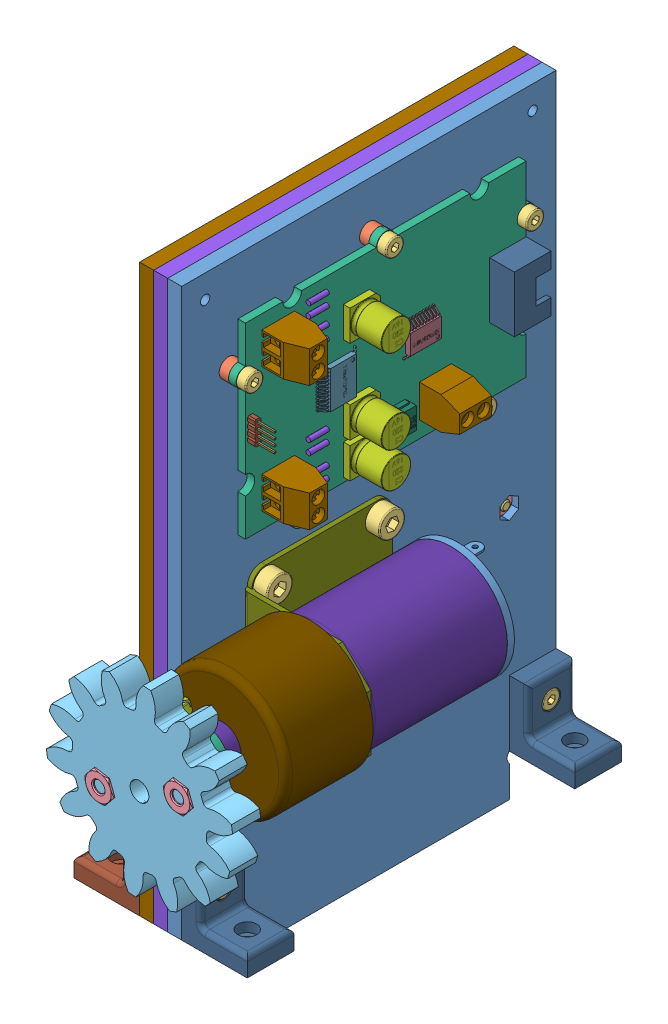
SolidWorks assembly moteur-complet, configuration Défaut. Lengths in mm.
Overall size (62.95 130 103.93).
88 component instances, 29 part files, 109 mates.
Components (placement in the parent):
- moteur-platine-1-4: moteur-platine-1 [Défaut] at (-59.9962 -68.9698 170) size (3 130 80)
- Grove button-1: Grove button [Défaut] at (-66.7015 -12.8903 110) x (0 -1 0) z (0 0 -1) size (20 11.6 23.6)
  - PCB grove 20x20-1: PCB grove 20x20 [Défaut] at (2.0795 1.2947 0) size (20 1.6 23.6)
  - 603 resistor 102-1: 603 resistor 102 [Default] at (2.0895 2.8947 -6.319) x (0 0 1) z (-1 0 0) size (2.36 0.62 1.03)
  - tactileswitch-CMS-1: tactileswitch-CMS [Default] at (-2.4169 2.8947 0.0035) x (0 0 1) z (-1 0 0) size (8.41 4.95 6.01)
  - Connecteur Grove (droit CMS)-1: Connecteur Grove (droit CMS) [Défaut] at (5.0795 2.8947 0) x (-1 0 0) z (0 1 0) size (6.5 14 10)
  - 603 resistor 102-2: 603 resistor 102 [Default] at (3.5895 2.8947 -6.319) x (0 0 1) z (-1 0 0) size (2.36 0.62 1.03)
- Grove I2C Motor driver TB6612FNG-1: Grove I2C Motor driver TB6612FNG [Défaut] at (-118.1962 28.5169 135.6463) x (0 0 1) z (1 0 0) size (64 44 12.2)
  - Plaque de base-1: Plaque de base [Défaut] at (-5.6463 -2.5133 63.2) size (64 44 1.6)
  - CS 220 16V-1: CS 220 16V [Défaut] at (0.1237 13.2167 64.8) x (1 0 0) z (0 -1 0) size (6.54 8.01 6.54)
  - CS 220 16V-2: CS 220 16V [Défaut] at (0.1237 5.6767 64.8) x (1 0 0) z (0 -1 0) size (6.54 8.01 6.54)
  - CS 220 16V-3: CS 220 16V [Défaut] at (0.1237 -12.2433 64.8) x (1 0 0) z (0 -1 0) size (6.54 8.01 6.54)
  - D1-1: D1 [Défaut] at (7.4081 5.2819 65.3) x (0 0.946795 -0.321836) z (1 0 0) size (1 1 4)
  - D1-2: D1 [Défaut] at (7.4081 7.7235 65.3) x (0 0.786026 0.618193) z (1 0 0) size (1 1 4)
  - D1-3: D1 [Défaut] at (7.4081 14.4025 65.3) x (0 0.953842 0.300308) z (1 0 0) size (1 1 4)
  - D1-4: D1 [Défaut] at (7.4081 11.9602 65.3) x (0 0.659384 0.751806) z (1 0 0) size (1 1 4)
  - D1-5: D1 [Défaut] at (7.4081 -17.5815 65.3) x (0 -0.999835 -0.018161) z (1 0 0) size (1 1 4)
  - D1-6: D1 [Défaut] at (7.4081 -14.133 65.3) x (0 0.806812 -0.590809) z (1 0 0) size (1 1 4)
  - D1-7: D1 [Défaut] at (7.4081 -11.4343 65.3) x (0 -0.166774 0.985995) z (1 0 0) size (1 1 4)
  - D1-8: D1 [Défaut] at (7.4081 -20.0356 65.3) x (0 0.962631 -0.270816) z (1 0 0) size (1 1 4)
  - bornier double-1: bornier double [Défaut] at (20.8537 7.1995 64.8) x (0 1 0) z (1 0 0) size (6.8 12.2 7)
  - bornier double-2: bornier double [Défaut] at (-12.8463 13.9867 64.8) x (-1 0 0) z (0 1 0) size (6.8 12.2 7)
  - bornier double-3: bornier double [Défaut] at (20.8537 -19.5133 64.8) x (0 1 0) z (1 0 0) size (6.8 12.2 7)
  - Grove Connecteur-1: Grove Connecteur [Défaut] at (-37.0963 -2.5133 64.05) x (1 0 0) z (0 -1 0) size (7.8 5.3 12)
  - Bloc 4 pins male-1: Bloc 4 pins male [Défaut] at (23.2493 -0.7812 63.276) x (0 -1 0) z (0 0 1) size (5.08 1.27 7.62)
    - Pin_cmi2c_Base-1: Pin_cmi2c_Base [Défaut] at (-0.1729 -0.0306 1.524) size (1.27 1.27 1.52)
    - Pin_cmi2c-1: Pin_cmi2c [Défaut] at (-0.1729 0.1472 -0.762) x (1 0 0) z (0 -1 0) size (0.36 7.62 0.36)
    - Pin_cmi2c-2: Pin_cmi2c [Défaut] at (1.0971 0.1472 -0.762) x (1 0 0) z (0 -1 0) size (0.36 7.62 0.36)
    - Pin_cmi2c-3: Pin_cmi2c [Défaut] at (2.3671 0.1472 -0.762) x (1 0 0) z (0 -1 0) size (0.36 7.62 0.36)
    - Pin_cmi2c-4: Pin_cmi2c [Défaut] at (3.6371 0.1472 -0.762) x (1 0 0) z (0 -1 0) size (0.36 7.62 0.36)
    - Pin_cmi2c_Base-2: Pin_cmi2c_Base [Défaut] at (1.0971 -0.0306 1.524) size (1.27 1.27 1.52)
    - Pin_cmi2c_Base-3: Pin_cmi2c_Base [Défaut] at (2.3671 -0.0306 1.524) size (1.27 1.27 1.52)
    - Pin_cmi2c_Base-4: Pin_cmi2c_Base [Défaut] at (3.6371 -0.0306 1.524) size (1.27 1.27 1.52)
  - Microcontroller 32F030F4P6-1: Microcontroller 32F030F4P6 [Défaut] at (-12.4961 -2.5519 65.5199) size (6.61 6.93 1.72)
  - Microcontroller TB6612FNG-1: Microcontroller TB6612FNG [Défaut] at (5.1421 -2.7086 65.5199) x (0 1 0) z (0 0 1) size (8 8.26 1.72)
  - PK13-1: PK13 [Défaut] at (-8.5328 11.2953 64.8) x (0 -1 0) z (-1 0 0) size (5.33 2 3.32)
- moteur MFA-1: moteur MFA [Défaut] at (-44.4916 -13.5198 141.6132) x (0 0 -1) z (0 -1 0) size (69.13 27.9 30)
  - moteur-support-1: moteur-support [Défaut] at (-14.3868 -12.5047 0) size (31 26.4 30)
  - moteur-corps-1: moteur-corps [Défaut] at (14.8132 1.8953 0) x (0 0 1) z (-1 0 0) size (24 24 62.63)
  - moteur-capuchon-1: moteur-capuchon [Défaut] at (-15.3868 1.8953 0) x (0 0 1) z (-1 0 0) size (27 27 18.7)
  - moteur-arriere-1: moteur-arriere [Défaut] at (16.3132 1.8953 0) x (0 0 1) z (-1 0 0) size (24 24 6.5)
- entretoise-grove-1: entretoise-grove [Défaut] at (-54.9962 51.0302 130) x (0 0.271539 0.962428) z (-1 0 0) size (4 4 2)
- entretoise-grove-2: entretoise-grove [Défaut] at (-54.9962 41.0302 100) x (0 0.358036 0.933708) z (-1 0 0) size (4 4 2)
- entretoise-grove-3: entretoise-grove [Défaut] at (-54.9962 41.0302 160) x (0 -0.42455 0.905404) z (-1 0 0) size (4 4 2)
- entretoise-grove-4: entretoise-grove [Défaut] at (-54.9962 11.0302 150) x (0 0 1) z (-1 0 0) size (4 4 2)
- entretoise-grove-5: entretoise-grove [Défaut] at (-54.9962 11.0302 110) x (0 0.014886 0.999889) z (-1 0 0) size (4 4 2)
- entretoise-grove-6: entretoise-grove [Défaut] at (-67.9962 -14.9698 120) x (0 0.014606 -0.999893) z (1 0 0) size (4 4 2)
- entretoise-grove-7: entretoise-grove [Défaut] at (-67.9962 -14.9698 100) x (0 0.432952 0.901417) z (1 0 0) size (4 4 2)
- vis-chc-1: vis-chc [Vis CHC M2x12] at (-69.5962 -14.9698 100) x (0 0.697993 -0.716105) z (0 0.716105 0.697993) size (3.8 14 3.8)
- vis-chc-2: vis-chc [Vis CHC M2x12] at (-69.5962 -14.9698 120) x (0 0.185382 -0.982666) z (0 0.982666 0.185382) size (3.8 14 3.8)
- vis-chc-3: vis-chc [Vis CHC M2x12] at (-53.3962 41.0302 100) x (0 0.381849 -0.924225) z (0 -0.924225 -0.381849) size (3.8 14 3.8)
- vis-chc-4: vis-chc [Vis CHC M2x12] at (-53.3962 51.0302 130) x (0 0.381849 -0.924225) z (0 -0.924225 -0.381849) size (3.8 14 3.8)
- vis-chc-5: vis-chc [Vis CHC M2x12] at (-53.3962 41.0302 160) x (0 0.381849 -0.924225) z (0 -0.924225 -0.381849) size (3.8 14 3.8)
- vis-chc-6: vis-chc [Vis CHC M2x12] at (-53.3962 11.0302 150) x (0 0.381849 -0.924225) z (0 -0.924225 -0.381849) size (3.8 14 3.8)
- vis-chc-7: vis-chc [Vis CHC M2x12] at (-53.3962 11.0302 110) x (0 0.381849 -0.924225) z (0 -0.924225 -0.381849) size (3.8 14 3.8)
- ecrou-h-2: ecrou-h [6007 HU M2] at (-59.9962 -14.9698 120) x (0 0.866025 0.5) z (0 -0.5 0.866025) size (4 1.6 4.62)
- ecrou-h-3: ecrou-h [6007 HU M2] at (-59.9962 -14.9698 100) x (0 0 1) z (0 -1 0) size (4 1.6 4.62)
- ecrou-h-4: ecrou-h [6007 HU M2] at (-64.5962 11.0302 110) x (0 0.866025 0.5) z (0 -0.5 0.866025) size (4 1.6 4.62)
- ecrou-h-5: ecrou-h [6007 HU M2] at (-64.5962 11.0302 150) x (0 0.866025 0.5) z (0 -0.5 0.866025) size (4 1.6 4.62)
- ecrou-h-6: ecrou-h [6007 HU M2] at (-64.5962 41.0302 160) x (0 0.866025 0.5) z (0 -0.5 0.866025) size (4 1.6 4.62)
- ecrou-h-7: ecrou-h [6007 HU M2] at (-64.5962 51.0302 130) x (0 0.866025 0.5) z (0 -0.5 0.866025) size (4 1.6 4.62)
- ecrou-h-8: ecrou-h [6007 HU M2] at (-64.5962 41.0302 100) x (0 0.866025 0.5) z (0 -0.5 0.866025) size (4 1.6 4.62)
- vis-chc-8: vis-chc [Vis CHC M3x10] at (-55.9962 -1.5198 129) x (0 0.773717 -0.633531) z (0 -0.633531 -0.773717) size (5.5 13 5.5)
- vis-chc-9: vis-chc [Vis CHC M3x10] at (-55.9962 -1.5198 153) x (0 0.483049 -0.875594) z (0 -0.875594 -0.483049) size (5.5 13 5.5)
- vis-chc-10: vis-chc [Vis CHC M3x10] at (-55.9962 -25.5198 153) x (0 0.381849 -0.924225) z (0 -0.924225 -0.381849) size (5.5 13 5.5)
- vis-chc-11: vis-chc [Vis CHC M3x10] at (-55.9962 -25.5198 129) x (0 0.381849 -0.924225) z (0 -0.924225 -0.381849) size (5.5 13 5.5)
- ecrou-h-9: ecrou-h [6012 HU M3] at (-65.3962 -1.5198 153) x (0 0.866025 0.5) z (0 -0.5 0.866025) size (5.5 2.4 6.35)
- ecrou-h-10: ecrou-h [6012 HU M3] at (-65.3962 -25.5198 153) x (0 0.866025 0.5) z (0 -0.5 0.866025) size (5.5 2.4 6.35)
- ecrou-h-11: ecrou-h [6012 HU M3] at (-65.3962 -25.5198 129) x (0 0.866025 -0.5) z (0 0.5 0.866025) size (5.5 2.4 6.35)
- ecrou-h-12: ecrou-h [6012 HU M3] at (-65.3962 -1.5198 129) x (0 0.866025 -0.5) z (0 0.5 0.866025) size (5.5 2.4 6.35)
- vis-chc-14: vis-chc [Vis CHC M2x16] at (-54.9962 -50.9698 95) x (0 -0.431797 -0.901971) z (0 -0.901971 0.431797) size (3.8 18 3.8)
- vis-chc-15: vis-chc [Vis CHC M2x16] at (-54.9962 -50.9698 165) x (0 0.381849 -0.924225) z (0 -0.924225 -0.381849) size (3.8 18 3.8)
- ecrou-h-15: ecrou-h [6007 HU M2] at (-69.5962 -50.9698 165) x (0 1 0) z (0 0 1) size (4 1.6 4.62)
- ecrou-h-16: ecrou-h [6007 HU M2] at (-69.5962 -50.9698 95) x (0 0.5 0.866025) z (0 -0.866025 0.5) size (4 1.6 4.62)
- engrenage-complet-1: engrenage-complet [Défaut] at (-42.1676 -13.7474 193.43) x (0.932852 0.36026 0) z (0 0 -1) size (39.32 40 14.86)
  - engrenage-1: engrenage [Défaut] at (1.0609 0.1936 0) size (39.32 40 6)
  - engrenage-bague_arret-1: engrenage-bague_arret [Défaut] at (-0.3178 -0.3667 13.5) x (-1 0 0) z (0 0 -1) size (24 24 8)
  - vis-tc-m3x6-1: vis-tc-m3x6 [Défaut] at (-0.3178 -8.4167 10.5) x (-0.611546 0 0.791209) z (0.791209 0 0.611546) size (5.5 7.83 5.5)
  - vis-chc-1: vis-chc [Vis CHC M3x8] at (-9.3178 -0.3667 7.5) x (0.40091 -0.916118 0) z (-0.916118 -0.40091 0) size (5.5 11 5.5)
  - vis-chc-2: vis-chc [Vis CHC M3x8] at (8.6822 -0.3667 7.5) x (0.998484 0.055044 0) z (0.055044 -0.998484 0) size (5.5 11 5.5)
  - ecrou-h-1: ecrou-h [6012 HU M3] at (8.6822 -0.3667 -0.4) x (1 0 0) z (0 1 0) size (5.5 2.4 6.35)
  - ecrou-h-2: ecrou-h [6012 HU M3] at (-9.3178 -0.3667 -0.4) x (1 0 0) z (0 1 0) size (5.5 2.4 6.35)
- moteur-platine-2-5: moteur-platine-2 [Défaut] at (-62.9962 -68.9698 170) size (3 130 80)
- moteur-platine-3-3: moteur-platine-3 [Défaut] at (-65.9962 -68.9698 170) size (3 130 80)
- equerre-3: equerre [Défaut] at (-56.9962 -59.9698 165) x (0 0 -1) z (1 0 0) size (10 14 14)
- equerre-2: equerre [Défaut] at (-56.9962 -59.9698 95) x (0 0 -1) z (1 0 0) size (10 14 14)
- equerre-ecrou-1: equerre-ecrou [Défaut] at (-65.9962 -59.9698 95) x (0 0 1) z (-1 0 0) size (10 14 14)
- equerre-ecrou-2: equerre-ecrou [Défaut] at (-65.9962 -59.9698 165) x (0 0 1) z (-1 0 0) size (10 14 14)
Mates (geometry in assembly coordinates):
- Coïncidente1: coincident anti-aligned: plane of moteur-platine-1-4 through (-56.9962 -61.1012 161.1314) normal (1 0 0); plane of moteur MFA-1/moteur-support-1 through (-56.9962 -25.5198 153) normal (-1 0 0)
- Coaxiale1: concentric anti-aligned: cylinder of moteur-platine-1-4 through (-59.9962 -1.5198 129) axis (1 0 0) radius 1.6; cylinder of moteur MFA-1/moteur-support-1 through (-30.5962 -1.5198 129) axis (-1 0 0) radius 1.65
- Coaxiale2: concentric anti-aligned: cylinder of moteur-platine-1-4 through (-59.9962 -25.5198 129) axis (1 0 0) radius 1.6; cylinder of moteur MFA-1/moteur-support-1 through (-30.5962 -25.5198 129) axis (-1 0 0) radius 1.65
- Parallèle1: parallel aligned: plane of moteur-platine-1-4 through (-56.9962 61.0302 90) normal (0 0 -1); plane of Grove I2C Motor driver TB6612FNG-1/Plaque de base-1 through (-53.3962 11.0302 100) normal (0 0 -1)
- Parallèle2: parallel aligned: plane of moteur-platine-1-4 through (-56.9962 61.0302 170) normal (0 1 0); plane of Grove I2C Motor driver TB6612FNG-1/Plaque de base-1 through (-53.3962 51.0302 132) normal (0 1 0)
- Coaxiale3: concentric anti-aligned: cylinder of Grove I2C Motor driver TB6612FNG-1/Plaque de base-1 through (-53.3962 11.0302 110) axis (-1 0 0) radius 1; cylinder of entretoise-grove-5 through (-56.9962 11.0302 110) axis (1 0 0) radius 1.1
- Coïncidente4: coincident anti-aligned: plane of Grove I2C Motor driver TB6612FNG-1/Plaque de base-1 through (-54.9962 21.0302 100) normal (-1 0 0); plane of entretoise-grove-5 through (-54.9962 11.0302 110) normal (1 0 0)
- Coaxiale4: concentric anti-aligned: cylinder of Grove I2C Motor driver TB6612FNG-1/Plaque de base-1 through (-53.3962 11.0302 150) axis (-1 0 0) radius 1; cylinder of entretoise-grove-4 through (-56.9962 11.0302 150) axis (1 0 0) radius 1.1
- Coïncidente5: coincident anti-aligned: plane of Grove I2C Motor driver TB6612FNG-1/Plaque de base-1 through (-54.9962 21.0302 100) normal (-1 0 0); plane of entretoise-grove-4 through (-54.9962 11.0302 150) normal (1 0 0)
- Coaxiale5: concentric anti-aligned: cylinder of Grove I2C Motor driver TB6612FNG-1/Plaque de base-1 through (-53.3962 41.0302 100) axis (-1 0 0) radius 1; cylinder of entretoise-grove-2 through (-56.9962 41.0302 100) axis (1 0 0) radius 1.1
- Coïncidente6: coincident anti-aligned: plane of Grove I2C Motor driver TB6612FNG-1/Plaque de base-1 through (-54.9962 21.0302 100) normal (-1 0 0); plane of entretoise-grove-2 through (-54.9962 41.0302 100) normal (1 0 0)
- Coaxiale6: concentric anti-aligned: cylinder of Grove I2C Motor driver TB6612FNG-1/Plaque de base-1 through (-53.3962 41.0302 160) axis (-1 0 0) radius 1; cylinder of entretoise-grove-3 through (-56.9962 41.0302 160) axis (1 0 0) radius 1.1
- Coïncidente7: coincident anti-aligned: plane of Grove I2C Motor driver TB6612FNG-1/Plaque de base-1 through (-54.9962 21.0302 100) normal (-1 0 0); plane of entretoise-grove-3 through (-54.9962 41.0302 160) normal (1 0 0)
- Coaxiale7: concentric anti-aligned: cylinder of Grove I2C Motor driver TB6612FNG-1/Plaque de base-1 through (-53.3962 51.0302 130) axis (-1 0 0) radius 1; cylinder of entretoise-grove-1 through (-56.9962 51.0302 130) axis (1 0 0) radius 1.1
- Coïncidente8: coincident anti-aligned: plane of Grove I2C Motor driver TB6612FNG-1/Plaque de base-1 through (-54.9962 21.0302 100) normal (-1 0 0); plane of entretoise-grove-1 through (-54.9962 51.0302 130) normal (1 0 0)
- Coïncidente9: coincident anti-aligned: plane of moteur-platine-1-4 through (-56.9962 -61.1012 161.1314) normal (1 0 0); plane of entretoise-grove-3 through (-56.9962 41.0302 160) normal (-1 0 0)
- Coaxiale8: concentric aligned: cylinder of moteur-platine-1-4 through (-59.9962 11.0302 150) axis (1 0 0) radius 1.1; cylinder of entretoise-grove-4 through (-56.9962 11.0302 150) axis (1 0 0) radius 1.1
- Coaxiale9: concentric anti-aligned: cylinder of Grove button-1/PCB grove 20x20-1 through (-69.5962 -14.9698 120) axis (1 0 0) radius 1.1; cylinder of entretoise-grove-6 through (-65.9962 -14.9698 120) axis (-1 0 0) radius 1.1
- Coaxiale10: concentric anti-aligned: cylinder of Grove button-1/PCB grove 20x20-1 through (-69.5962 -14.9698 100) axis (1 0 0) radius 1.1; cylinder of entretoise-grove-7 through (-65.9962 -14.9698 100) axis (-1 0 0) radius 1.1
- Coïncidente11: coincident anti-aligned: plane of Grove button-1/PCB grove 20x20-1 through (-67.9962 -14.9698 110) normal (1 0 0); plane of entretoise-grove-7 through (-67.9962 -14.9698 100) normal (-1 0 0)
- Coaxiale13: concentric anti-aligned: cylinder of moteur MFA-1/moteur-corps-1 through (-42.5962 -13.5198 189.43) axis (0 0 -1) radius 2; cylinder of engrenage-complet-1/engrenage-bague_arret-1 through (-42.5962 -13.5198 179.93) axis (0 0 1) radius 2.05
- Distance1: distance = 0.5 mm anti-aligned: plane of engrenage-complet-1/engrenage-bague_arret-1 through (-42.5962 -13.5198 179.93) normal (0 0 -1); plane of moteur MFA-1/moteur-corps-1 through (-42.5962 -13.5198 179.43) normal (0 0 1)
- Coïncidente12: coincident anti-aligned: plane of moteur-platine-1-4 through (-59.9962 -61.1012 161.1314) normal (-1 0 0); plane of moteur-platine-2-5 through (-59.9962 -61.1012 161.1314) normal (1 0 0)
- Coïncidente13: coincident aligned: plane of moteur-platine-1-4 through (-56.9962 61.0302 170) normal (0 1 0); plane of moteur-platine-2-5 through (-59.9962 61.0302 170) normal (0 1 0)
- Coïncidente14: coincident aligned: plane of moteur-platine-1-4 through (-56.9962 61.0302 90) normal (0 0 -1); plane of moteur-platine-2-5 through (-59.9962 61.0302 90) normal (0 0 -1)
- Coïncidente15: coincident anti-aligned: plane of moteur-platine-2-5 through (-62.9962 -61.1012 161.1314) normal (-1 0 0); plane of moteur-platine-3-3 through (-62.9962 -61.1012 161.1314) normal (1 0 0)
- Coïncidente16: coincident aligned: plane of moteur-platine-2-5 through (-59.9962 61.0302 170) normal (0 1 0); plane of moteur-platine-3-3 through (-62.9962 61.0302 170) normal (0 1 0)
- Coïncidente17: coincident aligned: plane of moteur-platine-1-4 through (-56.9962 61.0302 90) normal (0 0 -1); plane of moteur-platine-3-3 through (-62.9962 61.0302 90) normal (0 0 -1)
- Coïncidente18: coincident anti-aligned: plane of entretoise-grove-7 through (-65.9962 -14.9698 100) normal (1 0 0); plane of moteur-platine-3-3 through (-65.9962 -61.1012 161.1314) normal (-1 0 0)
- Coïncidente19: coincident anti-aligned: plane of entretoise-grove-6 through (-65.9962 -14.9698 120) normal (1 0 0); plane of moteur-platine-3-3 through (-65.9962 -61.1012 161.1314) normal (-1 0 0)
- Coïncidente21: coincident anti-aligned: plane of Grove button-1/PCB grove 20x20-1 through (-69.5962 -14.9698 110) normal (-1 0 0); plane of vis-chc-2 through (-69.5962 -14.9698 120) normal (1 0 0)
- Coaxiale15: concentric aligned: cylinder of vis-chc-2 through (-57.5962 -14.9698 120) axis (-1 0 0) radius 1; cylinder of ecrou-h-2 through (-58.3962 -14.9698 120) axis (-1 0 0) radius 0.7835
- Parallèle4: parallel aligned: plane of moteur-platine-1-4 through (-56.9962 61.0302 90) normal (0 0 -1); plane of ecrou-h-2 through (-58.3962 -13.8151 118) normal (0 0 -1)
- Coïncidente25: coincident anti-aligned: plane of Grove button-1/PCB grove 20x20-1 through (-69.5962 -14.9698 110) normal (-1 0 0); plane of vis-chc-1 through (-69.5962 -14.9698 100) normal (1 0 0)
- Coaxiale17: concentric aligned: cylinder of vis-chc-1 through (-57.5962 -14.9698 100) axis (-1 0 0) radius 1; cylinder of ecrou-h-3 through (-58.3962 -14.9698 100) axis (-1 0 0) radius 0.7835
- Parallèle5: parallel aligned: plane of moteur-platine-1-4 through (-56.9962 61.0302 90) normal (0 0 -1); plane of ecrou-h-3 through (-58.3962 -13.8151 98) normal (0 0 -1)
- Coaxiale18: concentric anti-aligned: cylinder of Grove I2C Motor driver TB6612FNG-1/Plaque de base-1 through (-53.3962 11.0302 110) axis (-1 0 0) radius 1; cylinder of vis-chc-7 through (-65.3962 11.0302 110) axis (1 0 0) radius 1
- Coaxiale19: concentric anti-aligned: cylinder of Grove I2C Motor driver TB6612FNG-1/Plaque de base-1 through (-53.3962 11.0302 150) axis (-1 0 0) radius 1; cylinder of vis-chc-6 through (-65.3962 11.0302 150) axis (1 0 0) radius 1
- Coaxiale20: concentric anti-aligned: cylinder of Grove I2C Motor driver TB6612FNG-1/Plaque de base-1 through (-53.3962 41.0302 160) axis (-1 0 0) radius 1; cylinder of vis-chc-5 through (-65.3962 41.0302 160) axis (1 0 0) radius 1
- Coaxiale21: concentric anti-aligned: cylinder of Grove I2C Motor driver TB6612FNG-1/Plaque de base-1 through (-53.3962 51.0302 130) axis (-1 0 0) radius 1; cylinder of vis-chc-4 through (-65.3962 51.0302 130) axis (1 0 0) radius 1
- Coaxiale22: concentric anti-aligned: cylinder of Grove I2C Motor driver TB6612FNG-1/Plaque de base-1 through (-53.3962 41.0302 100) axis (-1 0 0) radius 1; cylinder of vis-chc-3 through (-65.3962 41.0302 100) axis (1 0 0) radius 1
- Coïncidente28: coincident anti-aligned: plane of Grove I2C Motor driver TB6612FNG-1/Plaque de base-1 through (-53.3962 21.0302 100) normal (1 0 0); plane of vis-chc-3 through (-53.3962 41.0302 100) normal (-1 0 0)
- Coïncidente29: coincident anti-aligned: plane of Grove I2C Motor driver TB6612FNG-1/Plaque de base-1 through (-53.3962 21.0302 100) normal (1 0 0); plane of vis-chc-4 through (-53.3962 51.0302 130) normal (-1 0 0)
- Coïncidente30: coincident anti-aligned: plane of Grove I2C Motor driver TB6612FNG-1/Plaque de base-1 through (-53.3962 21.0302 100) normal (1 0 0); plane of vis-chc-5 through (-53.3962 41.0302 160) normal (-1 0 0)
- Coïncidente31: coincident anti-aligned: plane of Grove I2C Motor driver TB6612FNG-1/Plaque de base-1 through (-53.3962 21.0302 100) normal (1 0 0); plane of vis-chc-6 through (-53.3962 11.0302 150) normal (-1 0 0)
- Coïncidente32: coincident anti-aligned: plane of Grove I2C Motor driver TB6612FNG-1/Plaque de base-1 through (-53.3962 21.0302 100) normal (1 0 0); plane of vis-chc-7 through (-53.3962 11.0302 110) normal (-1 0 0)
- Coaxiale23: concentric anti-aligned: cylinder of vis-chc-7 through (-65.3962 11.0302 110) axis (1 0 0) radius 1; cylinder of ecrou-h-4 through (-62.9962 11.0302 110) axis (-1 0 0) radius 0.7835
- Coaxiale24: concentric anti-aligned: cylinder of vis-chc-3 through (-65.3962 41.0302 100) axis (1 0 0) radius 1; cylinder of ecrou-h-8 through (-62.9962 41.0302 100) axis (-1 0 0) radius 0.7835
- Coaxiale25: concentric anti-aligned: cylinder of vis-chc-4 through (-65.3962 51.0302 130) axis (1 0 0) radius 1; cylinder of ecrou-h-7 through (-62.9962 51.0302 130) axis (-1 0 0) radius 0.7835
- Coaxiale26: concentric anti-aligned: cylinder of vis-chc-5 through (-65.3962 41.0302 160) axis (1 0 0) radius 1; cylinder of ecrou-h-6 through (-62.9962 41.0302 160) axis (-1 0 0) radius 0.7835
- Coaxiale27: concentric anti-aligned: cylinder of vis-chc-6 through (-65.3962 11.0302 150) axis (1 0 0) radius 1; cylinder of ecrou-h-5 through (-62.9962 11.0302 150) axis (-1 0 0) radius 0.7835
- Parallèle6: parallel aligned: plane of moteur-platine-3-3 through (-62.9962 -59.9698 170) normal (0 0 1); plane of ecrou-h-6 through (-62.9962 39.8755 162) normal (0 0 1)
- Parallèle7: parallel aligned: plane of moteur-platine-3-3 through (-62.9962 -59.9698 170) normal (0 0 1); plane of ecrou-h-7 through (-62.9962 49.8755 132) normal (0 0 1)
- Parallèle8: parallel aligned: plane of moteur-platine-3-3 through (-62.9962 -59.9698 170) normal (0 0 1); plane of ecrou-h-8 through (-62.9962 39.8755 102) normal (0 0 1)
- Parallèle9: parallel aligned: plane of moteur-platine-3-3 through (-62.9962 -59.9698 170) normal (0 0 1); plane of ecrou-h-5 through (-62.9962 9.8755 152) normal (0 0 1)
- Parallèle10: parallel aligned: plane of moteur-platine-3-3 through (-62.9962 -59.9698 170) normal (0 0 1); plane of ecrou-h-4 through (-62.9962 9.8755 112) normal (0 0 1)
- Coaxiale28: concentric anti-aligned: cylinder of moteur MFA-1/moteur-support-1 through (-30.5962 -1.5198 153) axis (-1 0 0) radius 1.65; cylinder of vis-chc-9 through (-65.9962 -1.5198 153) axis (1 0 0) radius 1.5
- Coaxiale29: concentric anti-aligned: cylinder of moteur MFA-1/moteur-support-1 through (-30.5962 -1.5198 129) axis (-1 0 0) radius 1.65; cylinder of vis-chc-8 through (-65.9962 -1.5198 129) axis (1 0 0) radius 1.5
- Coaxiale30: concentric anti-aligned: cylinder of moteur MFA-1/moteur-support-1 through (-30.5962 -25.5198 129) axis (-1 0 0) radius 1.65; cylinder of vis-chc-11 through (-65.9962 -25.5198 129) axis (1 0 0) radius 1.5
- Coaxiale31: concentric anti-aligned: cylinder of moteur MFA-1/moteur-support-1 through (-30.5962 -25.5198 153) axis (-1 0 0) radius 1.65; cylinder of vis-chc-10 through (-65.9962 -25.5198 153) axis (1 0 0) radius 1.5
- Coïncidente43: coincident anti-aligned: plane of moteur MFA-1/moteur-support-1 through (-55.9962 -29.752 156) normal (1 0 0); plane of vis-chc-11 through (-55.9962 -25.5198 129) normal (-1 0 0)
- Coïncidente44: coincident aligned: plane of moteur MFA-1/moteur-support-1 through (-55.9962 -29.752 156) normal (1 0 0); circle of vis-chc-10
- Coïncidente45: coincident anti-aligned: plane of moteur MFA-1/moteur-support-1 through (-55.9962 -29.752 156) normal (1 0 0); plane of vis-chc-8 through (-55.9962 -1.5198 129) normal (-1 0 0)
- Coïncidente46: coincident anti-aligned: plane of moteur MFA-1/moteur-support-1 through (-55.9962 -29.752 156) normal (1 0 0); plane of vis-chc-9 through (-55.9962 -1.5198 153) normal (-1 0 0)
- Coaxiale32: concentric anti-aligned: cylinder of vis-chc-8 through (-65.9962 -1.5198 129) axis (1 0 0) radius 1.5; cylinder of ecrou-h-12 through (-62.9962 -1.5198 129) axis (-1 0 0) radius 1.2295
- Coaxiale33: concentric anti-aligned: cylinder of vis-chc-10 through (-65.9962 -25.5198 153) axis (1 0 0) radius 1.5; cylinder of ecrou-h-10 through (-62.9962 -25.5198 153) axis (-1 0 0) radius 1.2295
- Coaxiale34: concentric anti-aligned: cylinder of vis-chc-9 through (-65.9962 -1.5198 153) axis (1 0 0) radius 1.5; cylinder of ecrou-h-9 through (-62.9962 -1.5198 153) axis (-1 0 0) radius 1.2295
- Coaxiale35: concentric anti-aligned: cylinder of vis-chc-11 through (-65.9962 -25.5198 129) axis (1 0 0) radius 1.5; cylinder of ecrou-h-11 through (-62.9962 -25.5198 129) axis (-1 0 0) radius 1.2295
- Parallèle11: parallel aligned: plane of moteur-platine-3-3 through (-62.9962 -59.9698 170) normal (0 0 1); plane of ecrou-h-10 through (-62.9962 -27.1075 155.75) normal (0 0 1)
- Parallèle12: parallel aligned: plane of moteur-platine-3-3 through (-62.9962 -59.9698 170) normal (0 0 1); plane of ecrou-h-11 through (-62.9962 -27.1075 131.75) normal (0 0 1)
- Parallèle13: parallel aligned: plane of moteur-platine-3-3 through (-62.9962 -59.9698 170) normal (0 0 1); plane of ecrou-h-12 through (-62.9962 -3.1075 131.75) normal (0 0 1)
- Parallèle14: parallel aligned: plane of moteur-platine-3-3 through (-62.9962 -59.9698 170) normal (0 0 1); plane of ecrou-h-9 through (-62.9962 -3.1075 155.75) normal (0 0 1)
- Coïncidente62: coincident anti-aligned: plane of moteur-platine-1-4 through (-56.9962 -61.1012 161.1314) normal (1 0 0); plane of equerre-2 through (-56.9962 -59.9698 95) normal (-1 0 0)
- Coaxiale41: concentric aligned: cylinder of moteur-platine-1-4 through (-59.9962 -50.9698 95) axis (1 0 0) radius 1.1; cylinder of equerre-2 through (-56.9962 -50.9698 95) axis (1 0 0) radius 1.1
- Coïncidente63: coincident aligned: plane of moteur-platine-1-4 through (-56.9962 -59.9698 97.7373) normal (0 -1 0); plane of equerre-2 through (-52.9962 -59.9698 100) normal (0 -1 0)
- Coaxiale42: concentric aligned: cylinder of moteur-platine-1-4 through (-59.9962 -50.9698 165) axis (1 0 0) radius 1.1; cylinder of equerre-3 through (-56.9962 -50.9698 165) axis (1 0 0) radius 1.1
- Coïncidente64: coincident aligned: plane of moteur-platine-1-4 through (-56.9962 -59.9698 162.2627) normal (0 -1 0); plane of equerre-3 through (-52.9962 -59.9698 170) normal (0 -1 0)
- Coïncidente65: coincident anti-aligned: plane of moteur-platine-1-4 through (-56.9962 -61.1012 161.1314) normal (1 0 0); plane of equerre-3 through (-56.9962 -59.9698 165) normal (-1 0 0)
- Coaxiale43: concentric aligned: cylinder of vis-chc-15 through (-70.9962 -50.9698 165) axis (1 0 0) radius 1; cylinder of equerre-3 through (-56.9962 -50.9698 165) axis (1 0 0) radius 1.1
- Coïncidente66: coincident anti-aligned: plane of vis-chc-15 through (-54.9962 -50.9698 165) normal (-1 0 0); plane of equerre-3 through (-54.9962 -50.9698 165) normal (1 0 0)
- Coaxiale44: concentric aligned: cylinder of vis-chc-14 through (-70.9962 -50.9698 95) axis (1 0 0) radius 1; cylinder of equerre-2 through (-56.9962 -50.9698 95) axis (1 0 0) radius 1.1
- Coïncidente67: coincident anti-aligned: plane of vis-chc-14 through (-54.9962 -50.9698 95) normal (-1 0 0); plane of equerre-2 through (-54.9962 -50.9698 95) normal (1 0 0)
- Coïncidente68: coincident anti-aligned: plane of moteur-platine-3-3 through (-65.9962 -61.1012 161.1314) normal (-1 0 0); plane of equerre-ecrou-2 through (-65.9962 -59.9698 165) normal (1 0 0)
- Coïncidente69: coincident anti-aligned: plane of moteur-platine-3-3 through (-65.9962 -61.1012 161.1314) normal (-1 0 0); plane of equerre-ecrou-1 through (-65.9962 -59.9698 95) normal (1 0 0)
- Coïncidente70: coincident aligned: plane of moteur-platine-3-3 through (-62.9962 -59.9698 97.7373) normal (0 -1 0); plane of equerre-ecrou-1 through (-69.9962 -59.9698 90) normal (0 -1 0)
- Coïncidente71: coincident aligned: plane of moteur-platine-3-3 through (-62.9962 -59.9698 97.7373) normal (0 -1 0); plane of equerre-ecrou-2 through (-69.9962 -59.9698 160) normal (0 -1 0)
- Coaxiale45: concentric anti-aligned: cylinder of vis-chc-14 through (-70.9962 -50.9698 95) axis (1 0 0) radius 1; cylinder of equerre-ecrou-1 through (-65.9962 -50.9698 95) axis (-1 0 0) radius 1.1
- Coaxiale46: concentric anti-aligned: cylinder of vis-chc-15 through (-70.9962 -50.9698 165) axis (1 0 0) radius 1; cylinder of equerre-ecrou-2 through (-65.9962 -50.9698 165) axis (-1 0 0) radius 1.1
- Coaxiale47: concentric anti-aligned: cylinder of vis-chc-15 through (-70.9962 -50.9698 165) axis (1 0 0) radius 1; cylinder of ecrou-h-15 through (-67.9962 -50.9698 165) axis (-1 0 0) radius 0.7835
- Parallèle18: parallel anti-aligned: plane of ecrou-h-15 through (-67.9962 -48.9698 166.1547) normal (0 1 0); plane of equerre-ecrou-2 through (-67.9962 -48.8047 166.25) normal (0 -1 0)
- Coïncidente73: coincident anti-aligned: plane of ecrou-h-15 through (-67.9962 -48.9698 163.8453) normal (1 0 0); plane of equerre-ecrou-2 through (-67.9962 -59.9698 165) normal (-1 0 0)
- Coaxiale49: concentric anti-aligned: cylinder of vis-chc-14 through (-70.9962 -50.9698 95) axis (1 0 0) radius 1; cylinder of ecrou-h-16 through (-67.9962 -50.9698 95) axis (-1 0 0) radius 0.7835
- Parallèle19: parallel anti-aligned: plane of ecrou-h-16 through (-67.9962 -48.9698 96.1547) normal (0 1 0); plane of equerre-ecrou-1 through (-67.9962 -48.8047 96.25) normal (0 -1 0)
- Coïncidente75: coincident anti-aligned: plane of ecrou-h-16 through (-67.9962 -48.9698 96.1547) normal (1 0 0); plane of equerre-ecrou-1 through (-67.9962 -59.9698 95) normal (-1 0 0)
- Coïncidente76: coincident anti-aligned: plane of ecrou-h-6 through (-62.9962 43.3396 160) normal (1 0 0); plane of moteur-platine-2-5 through (-62.9962 -61.1012 161.1314) normal (-1 0 0)
- Coïncidente77: coincident anti-aligned: plane of ecrou-h-5 through (-62.9962 13.3396 150) normal (1 0 0); plane of moteur-platine-2-5 through (-62.9962 -61.1012 161.1314) normal (-1 0 0)
- Coïncidente78: coincident anti-aligned: plane of ecrou-h-4 through (-62.9962 13.3396 110) normal (1 0 0); plane of moteur-platine-2-5 through (-62.9962 -61.1012 161.1314) normal (-1 0 0)
- Coïncidente79: coincident anti-aligned: plane of ecrou-h-8 through (-62.9962 43.3396 100) normal (1 0 0); plane of moteur-platine-2-5 through (-62.9962 -61.1012 161.1314) normal (-1 0 0)
- Coïncidente80: coincident anti-aligned: plane of ecrou-h-7 through (-62.9962 53.3396 130) normal (1 0 0); plane of moteur-platine-2-5 through (-62.9962 -61.1012 161.1314) normal (-1 0 0)
- Coïncidente81: coincident anti-aligned: plane of ecrou-h-12 through (-62.9962 0.0679 126.25) normal (1 0 0); plane of moteur-platine-2-5 through (-62.9962 -61.1012 161.1314) normal (-1 0 0)
- Coïncidente82: coincident anti-aligned: plane of ecrou-h-11 through (-62.9962 -23.9321 126.25) normal (1 0 0); plane of moteur-platine-2-5 through (-62.9962 -61.1012 161.1314) normal (-1 0 0)
- Coïncidente83: coincident anti-aligned: plane of ecrou-h-10 through (-62.9962 -22.3444 153) normal (1 0 0); plane of moteur-platine-2-5 through (-62.9962 -61.1012 161.1314) normal (-1 0 0)
- Coïncidente84: coincident anti-aligned: plane of ecrou-h-9 through (-62.9962 1.6556 153) normal (1 0 0); plane of moteur-platine-2-5 through (-62.9962 -61.1012 161.1314) normal (-1 0 0)
- Coaxiale50: concentric anti-aligned: cylinder of vis-chc-2 through (-57.5962 -14.9698 120) axis (-1 0 0) radius 1; cylinder of moteur-platine-3-3 through (-65.9962 -14.9698 120) axis (1 0 0) radius 1
- Coaxiale51: concentric anti-aligned: cylinder of vis-chc-1 through (-57.5962 -14.9698 100) axis (-1 0 0) radius 1; cylinder of moteur-platine-3-3 through (-65.9962 -14.9698 100) axis (1 0 0) radius 1
- Coïncidente85: coincident anti-aligned: plane of ecrou-h-3 through (-59.9962 -13.8151 102) normal (-1 0 0); plane of moteur-platine-2-5 through (-59.9962 -61.1012 161.1314) normal (1 0 0)
- Coïncidente86: coincident anti-aligned: plane of ecrou-h-2 through (-59.9962 -12.6604 120) normal (-1 0 0); plane of moteur-platine-2-5 through (-59.9962 -61.1012 161.1314) normal (1 0 0)
- Coaxiale52: concentric anti-aligned: cylinder of Grove button-1/PCB grove 20x20-1 through (-69.5962 -14.9698 100) axis (1 0 0) radius 1.1; cylinder of vis-chc-1 through (-57.5962 -14.9698 100) axis (-1 0 0) radius 1
- Coaxiale53: concentric anti-aligned: cylinder of Grove button-1/PCB grove 20x20-1 through (-69.5962 -14.9698 120) axis (1 0 0) radius 1.1; cylinder of vis-chc-2 through (-57.5962 -14.9698 120) axis (-1 0 0) radius 1
